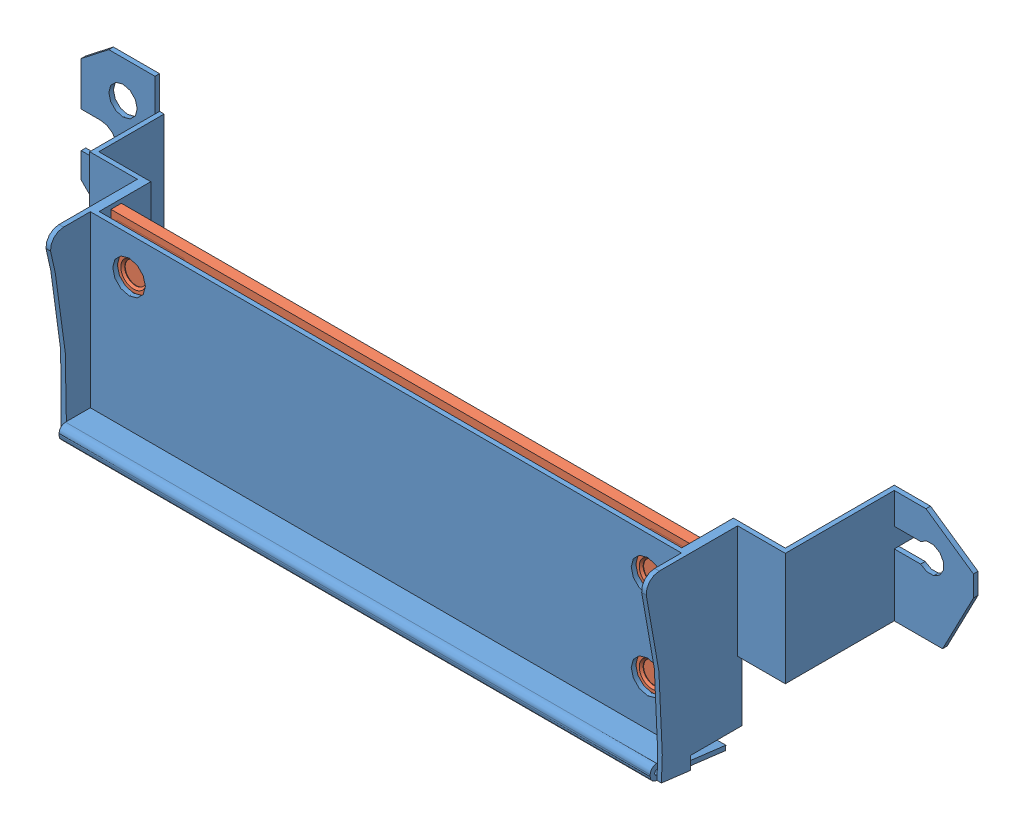
SolidWorks assembly 0400_ASM_LED_display, configuration Default. Lengths in mm.
Overall size (129.92 34.58 34.53).
2 component instances, 2 part files, 3 mates.
Components (placement in the parent):
- 0402 Wyświetlacz_płytka-1: 0402 Wyświetlacz_płytka [Default] at (42.4886 92.3828 40.377) size (129.92 34.58 34.53)
- 03_LED_display-2: 03_LED_display [Domyślna] at (-85.7255 175.5459 38.777) size (88.8 27.5 3.2)
Mates (geometry in assembly coordinates):
- Koncentryczne1: concentric aligned: circle of 0402 Wyświetlacz_płytka-1; circle of 03_LED_display-2
- Koncentryczne2: concentric aligned: circle of 0402 Wyświetlacz_płytka-1; circle of 03_LED_display-2
- Wspólnie1: coincident anti-aligned: plane of 0402 Wyświetlacz_płytka-1 through (42.4886 92.3828 40.377) normal (0 0 -1); plane of 03_LED_display-2 through (91.4395 87.2809 40.377) normal (0 0 1)
